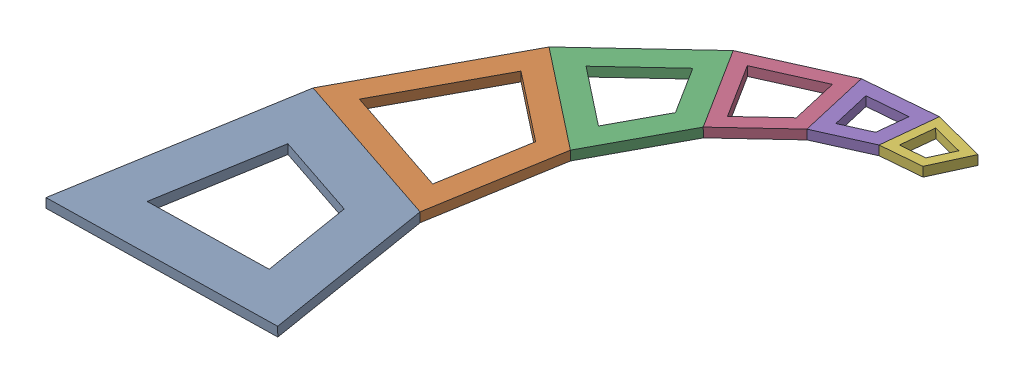
SolidWorks assembly sigle Curling Spiral (Outer Spine)_Assem, configuration Default. Lengths in mm.
Overall size (94.18 3.6 112.89).
6 component instances, 6 part files, 15 mates.
Components (placement in the parent):
- Spiral_1-1: Spiral_1 [Default] at (-16.342 9.2411 59.0905) x (0.999823 0.018827 -0.00003) z (-0.00003 0.003181 0.999995) size (50 2 49.3)
- Spiral_2-1: Spiral_2 [Default] at (-8.0237 9.2409 9.7852) x (0.944377 0.018828 0.328326) z (-0.328326 -0.003177 0.944559) size (37.51 2 36.99)
- Spiral_3-1: Spiral_3 [Default] at (10.0151 9.4759 -23.1058) x (0.784207 0.01674 0.620274) z (-0.620214 -0.009183 0.784379) size (28.14 2 27.75)
- Spiral_4-1: Spiral_4 [Default] at (30.8991 9.8091 -41.9698) x (0.537074 0.012797 0.843438) z (-0.843325 -0.014171 0.537217) size (21.11 2 20.82)
- Spiral_5-1: Spiral_5 [Default] at (50.3444 10.1491 -50.1923) x (0.230385 0.007434 0.973071) z (-0.972917 -0.017587 0.230483) size (15.84 2 15.62)
- Spiral_6-1: Spiral_6 [Default] at (66.1492 10.4435 -51.2282) x (-0.101853 0.001247 0.994799) z (-0.994621 -0.019053 -0.101811) size (11.88 2 11.72)
Mates (geometry in assembly coordinates):
- Coincident4: coincident anti-aligned: line of Spiral_1-1 through (27.4019 9.9471 22.1015) axis (-0.944377 -0.018828 -0.328326); line of Spiral_2-1 through (-8.0237 9.2409 9.7852) axis (0.944377 0.018828 0.328326)
- Coincident5: coincident: point of Spiral_1-1; point of Spiral_2-1
- Coincident6: coincident anti-aligned: line of Spiral_2-1 through (32.0852 9.947 -5.6493) axis (-0.784207 -0.01674 -0.620274); line of Spiral_3-1 through (10.0151 9.4759 -23.1058) axis (0.784207 0.01674 0.620274)
- Coincident7: coincident anti-aligned: line of Spiral_3-1 through (42.239 10.0793 -24.1613) axis (-0.537074 -0.012797 -0.843438); line of Spiral_4-1 through (30.8991 9.8091 -41.9698) axis (0.537074 0.012797 0.843438)
- Coincident8: coincident anti-aligned: line of Spiral_4-1 through (53.9939 10.2669 -34.7781) axis (-0.230385 -0.007434 -0.973071); line of Spiral_5-1 through (50.3444 10.1491 -50.1923) axis (0.230385 0.007434 0.973071)
- Coincident10: coincident: point of Spiral_2-1; point of Spiral_3-1
- Coincident11: coincident: point of Spiral_3-1; point of Spiral_4-1
- Coincident12: coincident: point of Spiral_4-1; point of Spiral_5-1
- Coincident63: coincident: line of Spiral_5-1 through (64.9387 10.4583 -39.4056) axis (0.101853 -0.001247 -0.994799); line of Spiral_6-1 through (66.1492 10.4435 -51.2282) axis (-0.101853 0.001247 0.994799)
- Coincident64: coincident: point of Spiral_5-1; point of Spiral_6-1
- Coincident66: coincident anti-aligned: plane of Spiral_1-1 through (27.3643 11.9468 22.0951) normal (0.328326 0.003177 -0.944559); plane of Spiral_2-1 through (-8.0613 11.2405 9.7789) normal (-0.328326 -0.003177 0.944559)
- Coincident67: coincident anti-aligned: plane of Spiral_2-1 through (32.0475 11.9467 -5.6557) normal (0.620214 0.009183 -0.784379); plane of Spiral_3-1 through (9.9774 11.4755 -23.1122) normal (-0.620214 -0.009183 0.784379)
- Coincident69: coincident anti-aligned: plane of Spiral_3-1 through (42.2014 12.079 -24.1676) normal (0.843325 0.014171 -0.537217); plane of Spiral_4-1 through (30.8615 11.8088 -41.9762) normal (-0.843325 -0.014171 0.537217)
- Coincident70: coincident anti-aligned: plane of Spiral_4-1 through (53.9562 12.2665 -34.7845) normal (0.972917 0.017587 -0.230483); plane of Spiral_5-1 through (50.3068 12.1488 -50.1987) normal (-0.972917 -0.017587 0.230483)
- Coincident71: coincident anti-aligned: plane of Spiral_5-1 through (64.9011 12.4579 -39.412) normal (0.994621 0.019053 0.101811); plane of Spiral_6-1 through (66.1115 12.4431 -51.2346) normal (-0.994621 -0.019053 -0.101811)
